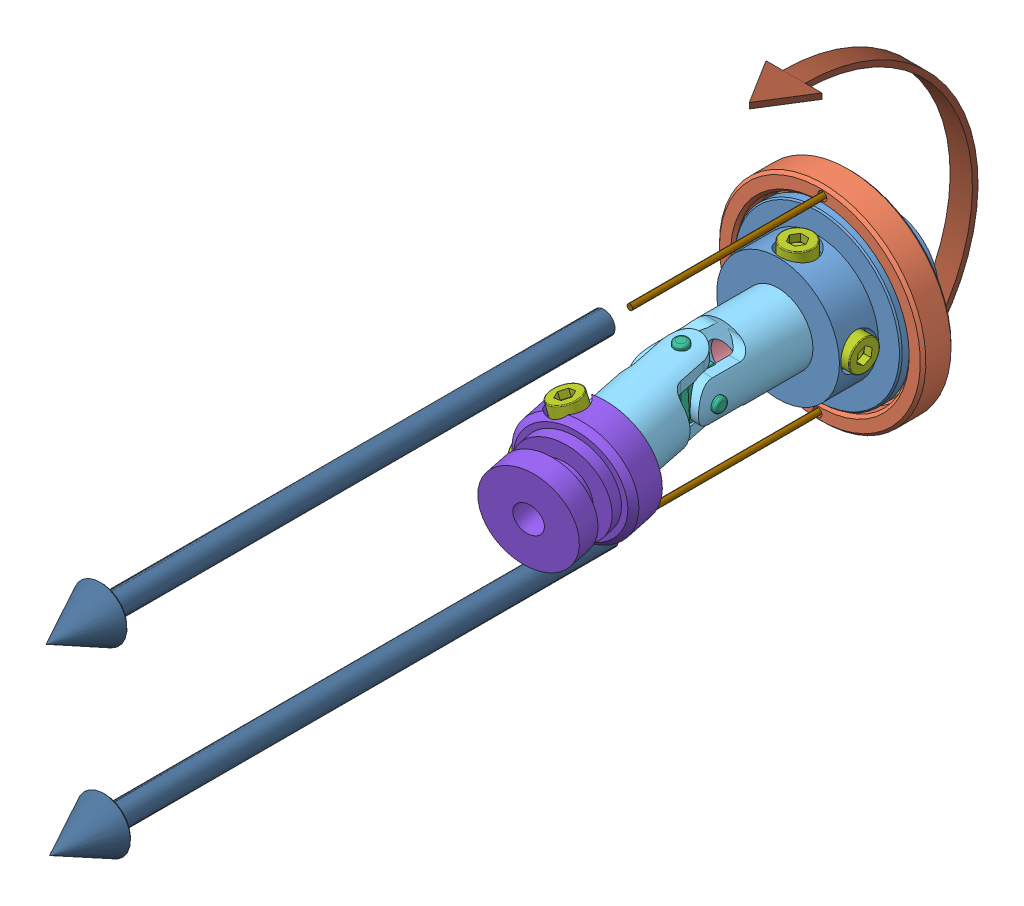
SolidWorks assembly acoplamento, configuration Default. Lengths in mm.
Overall size (37.95 59.89 168.53).
18 component instances, 11 part files, 30 mates.
Components (placement in the parent):
- fixo2-1: fixo2 [Default] at origin size (30 30 20.5)
- rotativo2-1: rotativo2 [Default] at (0 0 -4) x (-0.999665 0.025887 0) z (-0.025887 -0.999665 0) size (37 5.5 37)
- Needle Rollers Thrust Bearing_SKF-1: Needle Rollers Thrust Bearing_SKF [SKF - AXK 1730 - 20,DE,AC,20] at (0 0 -3) x (0 0 -1) z (0.981404 0.191954 0) size (2 30 30)
- encaixe-1: encaixe [Default] at (0 0 3.5) x (0 -1 0) z (-1 0 0) size (12.5 15 12.5)
- encaixe-2: encaixe [Default] at (3.0052 -1.5106 44.2222) x (0.255781 -0.960484 -0.10976) z (0.955555 0.268405 -0.121956) size (12.5 15 12.5)
- capa-1: capa [Default] at (0 0 6) x (-0.999888 0.014954 0) z (0.014954 0.999888 0) size (12.5 21.5 12.5)
- capa-2: capa [Default] at (2.6387 -1.3264 41.7561) x (0.014915 0.997273 0.07228) z (-0.989084 0.004117 0.147296) size (12.5 21.5 12.5)
- elo-1: elo [Default] at (-0.0032 -0.2168 26.9922) x (0.014915 0.997273 0.07228) z (-0.999888 0.014954 0) size (14 6 14)
- Socket Head Cap Screw_ISO-1: Socket Head Cap Screw_ISO [ISO 4762 M3 x 6 --- 6N] at (0 12 3.5) x (0 -1 0) z (0 0 1) size (9 5.5 5.5)
- Socket Head Cap Screw_ISO-2: Socket Head Cap Screw_ISO [ISO 4762 M3 x 6 --- 6N] at (12 0 3.5) x (-1 0 0) z (0 0.924225 0.381849) size (9 5.5 5.5)
- apoio_acopolamento2_-1: apoio_acopolamento2_ [Default] at (4.8377 -2.4317 56.5528) x (-0.955555 -0.268405 0.121956) z (0.255781 -0.960484 -0.10976) size (19.98 15 19.98)
- Socket Head Cap Screw_ISO-3: Socket Head Cap Screw_ISO [ISO 4762 M3 x 6 --- 6N] at (-7.5059 -4.4631 45.5637) x (0.955555 0.268405 -0.121956) z (0.12956 -0.010734 0.991513) size (9 5.5 5.5)
- Socket Head Cap Screw_ISO-4: Socket Head Cap Screw_ISO [ISO 4762 M3 x 6 --- 6N] at (0.1916 9.0547 45.4295) x (0.255781 -0.960484 -0.10976) z (-0.061179 -0.129391 0.989705) size (9 5.5 5.5)
- cabo-1: cabo [Default] at (0.4401 16.9943 -6) size (1 1 40)
- cabo-2: cabo [Default] at (-0.4401 -16.9943 -6) size (1 1 40)
- seta1-1: seta1 [Default] at (0.4401 16.9943 88.6448) x (0 0 -1) z (-0.414223 0.910175 0) size (100 9.67 9.67)
- seta-1: seta [Default] at (-3.0391 3.5771 1.1183) size (10 59.89 39)
- seta1-2: seta1 [Default] at (-0.4401 -16.9943 87.1242) x (0 0 -1) z (0.222474 0.974939 0) size (100 9.67 9.67)
Mates (geometry in assembly coordinates):
- Concentric1: concentric anti-aligned: cylinder of fixo2-1
- Tangent1: tangent anti-aligned: plane of fixo2-1 through (15 0 -2) normal (0 0 -1)
- Tangent2: tangent anti-aligned: unknown of rotativo2-1
- Concentric3: concentric aligned: cylinder of encaixe-2; cylinder of capa-2
- Coincident1: coincident anti-aligned: plane of encaixe-2 through (2.6387 -1.3264 41.7561) normal (-0.146597 0.073688 -0.986448); plane of capa-2 through (2.6387 -1.3264 41.7561) normal (0.146597 -0.073688 0.986448)
- Concentric4: concentric aligned: cylinder of encaixe-1; cylinder of capa-1
- Coincident2: coincident anti-aligned: plane of encaixe-1 through (0 0 6) normal (0 0 1); plane of capa-1 through (0 0 6) normal (0 0 -1)
- Concentric5: concentric aligned: cylinder of capa-2; cylinder of elo-1
- Symmetric1: symmetric aligned: plane of capa-2 through (2.6387 -1.3264 41.7561) normal (0.014915 0.997273 0.07228); plane of elo-1 through (0.1044 6.9809 24.506) normal (0.014915 0.997273 0.07228); plane of elo-1 through (-0.1044 -6.9809 23.494) normal (-0.014915 -0.997273 -0.07228)
- Concentric6: concentric anti-aligned: cylinder of capa-1; cylinder of elo-1
- Symmetric2: symmetric aligned: plane of capa-1 through (0 0 6) normal (-0.999888 0.014954 0); plane of elo-1 through (6.9992 -0.1047 24) normal (0.999888 -0.014954 0); plane of elo-1 through (-6.9992 0.1047 24) normal (-0.999888 0.014954 0)
- Concentric7: concentric anti-aligned: cylinder of fixo2-1; cylinder of encaixe-1
- Concentric8: concentric aligned: cylinder of fixo2-1; cylinder of encaixe-1
- Concentric91: concentric aligned: unknown of fixo2-1
- Coincident31: coincident anti-aligned: unknown of fixo2-1
- Concentric101: concentric aligned: unknown of fixo2-1
- Coincident41: coincident anti-aligned: unknown of fixo2-1
- Concentric102: concentric aligned: cylinder of fixo2-1; cylinder of rotativo2-1
- Concentric103: concentric anti-aligned: cylinder of encaixe-2; cylinder of apoio_acopolamento2_-1
- Concentric104: concentric aligned: cylinder of encaixe-2; cylinder of apoio_acopolamento2_-1
- Concentric105: concentric aligned: unknown of apoio_acopolamento2_-1
- Concentric106: concentric aligned: unknown of apoio_acopolamento2_-1
- Coincident43: coincident anti-aligned: unknown of apoio_acopolamento2_-1
- Coincident44: coincident anti-aligned: unknown of apoio_acopolamento2_-1
- Concentric107: concentric anti-aligned: cylinder of rotativo2-1; cylinder of cabo-1
- Concentric108: concentric anti-aligned: cylinder of rotativo2-1; cylinder of cabo-2
- Coincident45: coincident aligned: plane of rotativo2-1 through (-8.4972 0.22 -6) normal (0 0 -1); plane of cabo-1 through (0.4401 16.9943 -6) normal (0 0 -1)
- Coincident46: coincident aligned: plane of rotativo2-1 through (-8.4972 0.22 -6) normal (0 0 -1); plane of cabo-2 through (-0.4401 -16.9943 -6) normal (0 0 -1)
- Concentric109: concentric anti-aligned: cylinder of cabo-1; cylinder of seta1-1
- Concentric110: concentric anti-aligned: cylinder of cabo-2; cylinder of seta1-2
